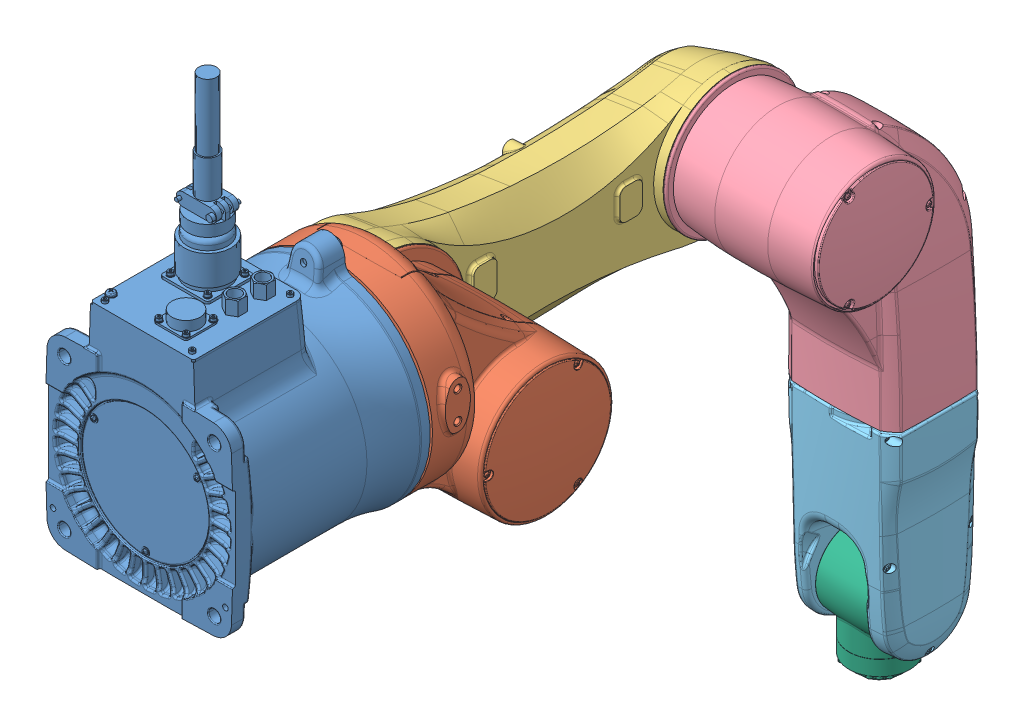
SolidWorks assembly VS-6577_asm, configuration Default. Lengths in mm.
Overall size (311.34 892.3 852.18).
6 component instances, 6 part files, 0 mates.
Components (placement in the parent):
- 410590-0050-c001-1: 410590-0050-c001 [Default] at origin size (231.28 447.69 211.18)
- 410590-0050-c002-1: 410590-0050-c002 [Default] at (0 0 -205.5) x (0 -1 0) z (1 0 0) size (274.79 240.99 246.58)
- 410590-0050-c003-1: 410590-0050-c003 [Default] at (-74.5 -75 -335) x (0 1 0) z (-1 0 0) size (174.88 523.08 125.78)
- 410590-0050-c004-1: 410590-0050-c004 [Default] at (-68 -75 -700) x (0 1 0) z (-1 0 0) size (290.54 222.14 158)
- 410590-0050-c005-1: 410590-0050-c005 [Default] at (0 -294 -790) x (-1 0 0) z (0 -1 0) size (122.18 118.59 254.51)
- 410590-0050-c006-1: 410590-0050-c006 [Default] at (0 -480 -790) x (0 1 0) z (-1 0 0) size (120.95 81.91 65)
